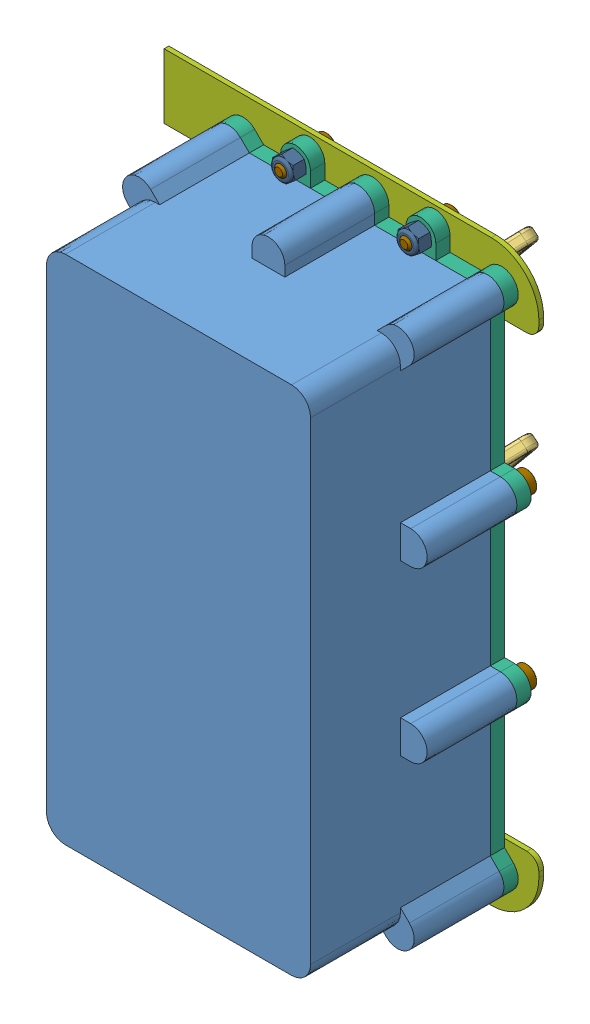
SolidWorks assembly EL-A0101-AA-TSMP + MS Assembly1, configuration Default. Lengths in mm.
Overall size (125.1 193.04 109.98).
49 component instances, 13 part files, 100 mates.
Components (placement in the parent):
- EL-50020-AA-TSMP + MS Enclosure1-1: EL-50020-AA-TSMP + MS Enclosure1 [Default] at (-164.5206 6 19.3259) size (106.02 188.57 59.98)
- EL-000XX-AA-Master Switch1-1: EL-000XX-AA-Master Switch1 [Default] at (-126.4206 74.6871 22.3259) x (-0.7694 0.638768 0) z (0 0 -1) size (57 57 72)
- EL-000XX-AA-Master Switch1-2: EL-000XX-AA-Master Switch1 [Default] at (-126.4206 134.4879 22.3259) x (-0.7694 0.638768 0) z (0 0 -1) size (57 57 72)
- EL-000XX-AA-Master Switch Key1-1: EL-000XX-AA-Master Switch Key1 [Default] at (-128.3369 72.3789 -20.6741) x (-0.7694 0.638768 0) z (0 0 -1) size (9.5 46.9 50)
- EL-000XX-AA-Master Switch Key1-2: EL-000XX-AA-Master Switch Key1 [Default] at (-128.3369 132.1797 -20.6741) x (-0.7694 0.638768 0) z (0 0 -1) size (9.5 46.9 50)
- EL-000XX-AA-Pomona Port (72930)1-1: EL-000XX-AA-Pomona Port (72930)1 [Pomona 72930 (BLACK)] at (-99.7506 103.75 23.6312) x (-0.945625 -0.325259 0) z (0.325259 -0.945625 0) size (14.73 33.88 17.01)
- EL-000XX-AA-Pomona Port (72930)1-2: EL-000XX-AA-Pomona Port (72930)1 [Pomona 72930 (BLACK)] at (-136.5806 23.4625 23.6312) x (0.758926 -0.651177 0) z (0.651177 0.758926 0) size (14.73 33.88 17.01)
- EL-000XX-AA-Pomona Port (72930)1-3: EL-000XX-AA-Pomona Port (72930)1 [Pomona 72930 (RED)] at (-116.2606 23.4625 23.6312) x (-0.998131 0.061106 0) z (-0.061106 -0.998131 0) size (14.73 33.88 17.01)
- EL-500XX-AA-TSMP Cover1-1: EL-500XX-AA-TSMP Cover1 [Default] at (-126.4206 23.4625 8.2134) x (0 0 -1) z (0 -1 0) size (13.97 71.12 30.48)
- EL-60022-AA-Enclosure Lid1-1: EL-60022-AA-Enclosure Lid1 [Default] at (-182.2706 162.971 19.3259) size (106.02 190.75 4.76)
- EL-30021-AA-Enclosure Mounts1-2: EL-30021-AA-Enclosure Mounts1 [Default] at (-133.0715 -19.9201 -386.9408) x (-1 0 0) z (0 0 -1) size (125.1 193.04 1.59)
- FS-Heat Set Insert, M4x7-4.7 (94180A351)-1: FS-Heat Set Insert, M4x7-4.7 (94180A351) [94180A351] at (-169.612 0.9086 21.6759) x (-0.721495 0.69242 0) z (0 0 -1) size (6.35 6.35 4.7)
- BR-Black Oxide C12.9 SHCS, M4x0.7-12 (91290A148)1-1: BR-Black Oxide C12.9 SHCS, M4x0.7-12 (91290A148)1 [91290A148] at (-169.612 0.9086 16.9759) x (0.909602 0.41548 0) z (0 0 -1) size (7 7 16.17)
- FS-Heat Set Insert, M4x7-4.7 (94180A351)-3: FS-Heat Set Insert, M4x7-4.7 (94180A351) [94180A351] at (-126.4206 -3.4097 21.6759) x (-0.990071 -0.140566 0) z (0 0 -1) size (6.35 6.35 4.7)
- BR-Black Oxide C12.9 SHCS, M4x0.7-12 (91290A148)1-3: BR-Black Oxide C12.9 SHCS, M4x0.7-12 (91290A148)1 [91290A148] at (-126.4206 -3.4097 16.9759) x (-1 0 0) z (0 0 -1) size (7 7 16.17)
- FS-Heat Set Insert, M4x7-4.7 (94180A351)-7: FS-Heat Set Insert, M4x7-4.7 (94180A351) [94180A351] at (-173.9303 57.181 21.6759) x (0.930432 0.366464 0) z (0 0 -1) size (6.35 6.35 4.7)
- BR-Black Oxide C12.9 SHCS, M4x0.7-12 (91290A148)1-7: BR-Black Oxide C12.9 SHCS, M4x0.7-12 (91290A148)1 [91290A148] at (-173.9303 57.181 18.5634) x (0.651659 -0.758512 0) z (0 0 -1) size (7 7 16.17)
- BR-Black Oxide C12.9 SHCS, M4x0.7-12 (91290A148)1-12: BR-Black Oxide C12.9 SHCS, M4x0.7-12 (91290A148)1 [91290A148] at (-147.3316 175.75 16.9759) x (0.218887 -0.97575 0) z (0 0 -1) size (7 7 16.17)
- BR-Black Oxide C12.9 SHCS, M4x0.7-12 (91290A148)1-13: BR-Black Oxide C12.9 SHCS, M4x0.7-12 (91290A148)1 [91290A148] at (-147.3316 -5 16.9759) x (-0.84991 0.526928 0) z (0 0 -1) size (7 7 16.17)
- BR-Black Oxide C12.9 SHCS, M4x0.7-12 (91290A148)1-14: BR-Black Oxide C12.9 SHCS, M4x0.7-12 (91290A148)1 [91290A148] at (-105.5097 -5 16.9759) x (-0.836932 0.547307 0) z (0 0 -1) size (7 7 16.17)
- FS-NYLOC C8 HX, M4x0.7-5 (90576A103)1-1: FS-NYLOC C8 HX, M4x0.7-5 (90576A103)1 [90576A103] at (-147.3316 -5 21.8259) size (7 8.08 5)
- FS-NYLOC C8 HX, M4x0.7-5 (90576A103)1-2: FS-NYLOC C8 HX, M4x0.7-5 (90576A103)1 [90576A103] at (-147.3316 175.75 21.8259) x (0.639392 -0.768881 0) z (0 0 1) size (7 8.08 5)
- FS-NYLOC C8 HX, M4x0.7-5 (90576A103)1-3: FS-NYLOC C8 HX, M4x0.7-5 (90576A103)1 [90576A103] at (-105.5097 -5 21.8259) x (0.821981 0.569515 0) z (0 0 1) size (7 8.08 5)
- EL-Steel Nylon Locknut, C8, M6x1-6 (90576A115)1-1: EL-Steel Nylon Locknut, C8, M6x1-6 (90576A115)1 [90576A115] at (-140.6545 146.3051 28.3259) x (0.999355 0.03592 0) z (0 0 1) size (10 11.55 6)
- EL-Steel Nylon Locknut, C8, M6x1-6 (90576A115)1-2: EL-Steel Nylon Locknut, C8, M6x1-6 (90576A115)1 [90576A115] at (-112.1867 122.6707 28.3259) x (-0.960335 0.278849 0) z (0 0 1) size (10 11.55 6)
- EL-BLACK OXIDE C12.9 SHCP, M6x1-22 (91290A328)1-1: EL-BLACK OXIDE C12.9 SHCP, M6x1-22 (91290A328)1 [91290A328] at (-112.1867 122.6707 22.5634) x (-1 0 0) z (0 0 -1) size (10 10 28.07)
- EL-BLACK OXIDE C12.9 SHCP, M6x1-22 (91290A328)1-2: EL-BLACK OXIDE C12.9 SHCP, M6x1-22 (91290A328)1 [91290A328] at (-140.6545 146.3051 22.5634) x (-0.99792 -0.064462 0) z (0 0 -1) size (10 10 28.07)
- EL-BLACK OXIDE C12.9 SHCP, M6x1-22 (91290A328)1-3: EL-BLACK OXIDE C12.9 SHCP, M6x1-22 (91290A328)1 [91290A328] at (-112.1867 62.8699 22.5634) x (-0.99792 -0.064462 0) z (0 0 -1) size (10 10 28.07)
- EL-BLACK OXIDE C12.9 SHCP, M6x1-22 (91290A328)1-4: EL-BLACK OXIDE C12.9 SHCP, M6x1-22 (91290A328)1 [91290A328] at (-140.6545 86.5043 22.5634) x (-0.99792 -0.064462 0) z (0 0 -1) size (10 10 28.07)
- EL-Steel Nylon Locknut, C8, M6x1-6 (90576A115)1-3: EL-Steel Nylon Locknut, C8, M6x1-6 (90576A115)1 [90576A115] at (-112.1867 62.8699 28.3259) x (-0.427051 0.904227 0) z (0 0 1) size (10 11.55 6)
- EL-Steel Nylon Locknut, C8, M6x1-6 (90576A115)1-4: EL-Steel Nylon Locknut, C8, M6x1-6 (90576A115)1 [90576A115] at (-140.6545 86.5043 28.3259) x (-0.279494 0.960147 0) z (0 0 1) size (10 11.55 6)
- BR-Black Oxide C12.9 SHCS, M4x0.7-12 (91290A148)1-15: BR-Black Oxide C12.9 SHCS, M4x0.7-12 (91290A148)1 [91290A148] at (-105.5097 175.75 16.9759) x (0.462086 -0.886835 0) z (0 0 -1) size (7 7 16.17)
- FS-NYLOC C8 HX, M4x0.7-5 (90576A103)1-4: FS-NYLOC C8 HX, M4x0.7-5 (90576A103)1 [90576A103] at (-105.5097 175.75 21.8259) x (-0.393684 -0.919246 0) z (0 0 1) size (7 8.08 5)
- FS-PLASTIC-HEAD THUMB SCREW, M4x0.7-10 (96016A8431-3: FS-PLASTIC-HEAD THUMB SCREW, M4x0.7-10 (96016A8431 [Default] at (-154.3606 23.4625 13.0034) x (0 0 1) z (1 0 0) size (15.5 13 13)
- FS-PLASTIC-HEAD THUMB SCREW, M4x0.7-10 (96016A8431-4: FS-PLASTIC-HEAD THUMB SCREW, M4x0.7-10 (96016A8431 [Default] at (-98.4806 23.4625 13.0034) x (0 0 1) z (1 0 0) size (15.5 13 13)
- FS-Heat Set Insert, M4x7-4.7 (94180A351)-2: FS-Heat Set Insert, M4x7-4.7 (94180A351) [94180A351] at (-83.2293 0.9086 21.6759) x (0.721495 0.69242 0) z (0 0 1) size (6.35 6.35 4.7)
- BR-Black Oxide C12.9 SHCS, M4x0.7-12 (91290A148)1-16: BR-Black Oxide C12.9 SHCS, M4x0.7-12 (91290A148)1 [91290A148] at (-83.2293 0.9086 16.9759) x (0.909602 -0.41548 0) z (0 0 -1) size (7 7 16.17)
- FS-Heat Set Insert, M4x7-4.7 (94180A351)-4: FS-Heat Set Insert, M4x7-4.7 (94180A351) [94180A351] at (-169.612 169.8414 21.6759) x (-0.721495 -0.69242 0) z (0 0 1) size (6.35 6.35 4.7)
- BR-Black Oxide C12.9 SHCS, M4x0.7-12 (91290A148)1-17: BR-Black Oxide C12.9 SHCS, M4x0.7-12 (91290A148)1 [91290A148] at (-169.612 169.8414 16.9759) x (-0.909602 0.41548 0) z (0 0 -1) size (7 7 16.17)
- FS-Heat Set Insert, M4x7-4.7 (94180A351)-5: FS-Heat Set Insert, M4x7-4.7 (94180A351) [94180A351] at (-126.4206 174.1597 21.6759) x (0.990071 -0.140566 0) z (0 0 1) size (6.35 6.35 4.7)
- BR-Black Oxide C12.9 SHCS, M4x0.7-12 (91290A148)1-18: BR-Black Oxide C12.9 SHCS, M4x0.7-12 (91290A148)1 [91290A148] at (-126.4206 174.1597 16.9759) x (1 0 0) z (0 0 -1) size (7 7 16.17)
- BR-Black Oxide C12.9 SHCS, M4x0.7-12 (91290A148)1-19: BR-Black Oxide C12.9 SHCS, M4x0.7-12 (91290A148)1 [91290A148] at (-83.2293 169.8414 16.9759) x (-0.909602 -0.41548 0) z (0 0 -1) size (7 7 16.17)
- FS-Heat Set Insert, M4x7-4.7 (94180A351)-6: FS-Heat Set Insert, M4x7-4.7 (94180A351) [94180A351] at (-83.2293 169.8414 21.6759) x (0.721495 -0.69242 0) z (0 0 -1) size (6.35 6.35 4.7)
- BR-Black Oxide C12.9 SHCS, M4x0.7-12 (91290A148)1-9: BR-Black Oxide C12.9 SHCS, M4x0.7-12 (91290A148)1 [91290A148] at (-173.9303 113.569 18.5634) x (0.651659 -0.758512 0) z (0 0 -1) size (7 7 16.17)
- FS-Heat Set Insert, M4x7-4.7 (94180A351)-9: FS-Heat Set Insert, M4x7-4.7 (94180A351) [94180A351] at (-173.9303 113.569 21.6759) x (0.930432 0.366464 0) z (0 0 -1) size (6.35 6.35 4.7)
- FS-Heat Set Insert, M4x7-4.7 (94180A351)-10: FS-Heat Set Insert, M4x7-4.7 (94180A351) [94180A351] at (-78.9109 57.181 21.6759) x (0.930432 -0.366464 0) z (0 0 1) size (6.35 6.35 4.7)
- BR-Black Oxide C12.9 SHCS, M4x0.7-12 (91290A148)1-20: BR-Black Oxide C12.9 SHCS, M4x0.7-12 (91290A148)1 [91290A148] at (-78.9109 57.181 18.5634) x (0.651659 0.758512 0) z (0 0 -1) size (7 7 16.17)
- FS-Heat Set Insert, M4x7-4.7 (94180A351)-11: FS-Heat Set Insert, M4x7-4.7 (94180A351) [94180A351] at (-78.9109 113.569 21.6759) x (0.930432 -0.366464 0) z (0 0 1) size (6.35 6.35 4.7)
- BR-Black Oxide C12.9 SHCS, M4x0.7-12 (91290A148)1-21: BR-Black Oxide C12.9 SHCS, M4x0.7-12 (91290A148)1 [91290A148] at (-78.9109 113.569 18.5634) x (0.651659 0.758512 0) z (0 0 -1) size (7 7 16.17)
Mates (geometry in assembly coordinates):
- Concentric12: concentric anti-aligned: cylinder of EL-000XX-AA-Master Switch-2 through (-126.4206 134.4879 19.3259) axis (0 0 -1) radius 5; cylinder of EL-000XX-AA-Master Switch Key-2 through (-126.4206 134.4879 -20.6741) axis (0 0 1) radius 4.75
- Coincident7: coincident anti-aligned: plane of EL-000XX-AA-Master Switch-2 through (-126.4206 134.4879 -10.6741) normal (0 0 -1); plane of EL-000XX-AA-Master Switch Key-2 through (-144.6836 109.359 -10.6741) normal (0 0 1)
- Parallel2: parallel: plane of EL-000XX-AA-Master Switch-2 through (-130.3193 131.3574 19.3259) normal (0.7694 -0.638768 0); line of EL-000XX-AA-Master Switch Key-2 through (-128.0152 129.4362 -11.6741) axis (-0.638768 -0.7694 0)
- Concentric18: concentric anti-aligned: cylinder of EL-800XX-BA-HVI Board-1 through (-55.9835 -25.4935 29.8055) axis (0 0 1) radius 2.1; cylinder of FS-NYLON SCREW BHCS, M4x0.7-6(94879A216)-1 through (-155.3975 139.0325 75.2021) axis (0 0 -1) radius 2
- Coincident14: coincident anti-aligned: plane of EL-800XX-BA-HVI Board-1 through (-11.47 -15.016 29.394) normal (0 0 -1); plane of FS-NYLON SCREW BHCS, M4x0.7-6(94879A216)-1 through (-155.3975 139.0325 75.2021) normal (0 0 1)
- Concentric21: concentric anti-aligned: cylinder of EL-000XX-AA-Master Switch-1 through (-126.4206 74.6871 19.3259) axis (0 0 -1) radius 5; cylinder of EL-000XX-AA-Master Switch Key-1 through (-126.4206 74.6871 -20.6741) axis (0 0 1) radius 4.75
- Parallel3: parallel anti-aligned: plane of EL-000XX-AA-Master Switch-1 through (-130.3193 71.5566 19.3259) normal (0.7694 -0.638768 0); plane of EL-000XX-AA-Master Switch Key-1 through (-129.8757 73.6564 -20.6741) normal (-0.7694 0.638768 0)
- Coincident18: coincident anti-aligned: plane of EL-000XX-AA-Master Switch-1 through (-126.4206 74.6871 -10.6741) normal (0 0 -1); plane of EL-000XX-AA-Master Switch Key-1 through (-144.6836 49.5582 -10.6741) normal (0 0 1)
- Concentric22: concentric aligned: cylinder of EL-500XX-AA-TSMP Cover-1 through (-154.3606 23.4625 10.7534) axis (0 0 -1) radius 2.4; cylinder of FS-PLASTIC-HEAD THUMB SCREW, M4x0.7-10 (96016A843-1 through (-154.3606 23.4625 5.2534) axis (0 0 -1) radius 2
- Coincident19: coincident anti-aligned: plane of EL-500XX-AA-TSMP Cover-1 through (-161.9806 13.3025 10.7534) normal (0 0 -1); plane of FS-PLASTIC-HEAD THUMB SCREW, M4x0.7-10 (96016A843-1 through (-151.1962 22.2191 10.7534) normal (0 0 1)
- Concentric23: concentric aligned: cylinder of EL-500XX-AA-TSMP Cover-1 through (-98.4806 23.4625 10.7534) axis (0 0 -1) radius 2.4; cylinder of FS-PLASTIC-HEAD THUMB SCREW, M4x0.7-10 (96016A843-2 through (-98.4806 23.4625 5.2534) axis (0 0 -1) radius 2
- Coincident20: coincident anti-aligned: plane of EL-500XX-AA-TSMP Cover-1 through (-90.8606 13.3025 10.7534) normal (0 0 -1); plane of FS-PLASTIC-HEAD THUMB SCREW, M4x0.7-10 (96016A843-2 through (-99.8556 26.5721 10.7534) normal (0 0 1)
- Coincident27: coincident anti-aligned: plane of EL-500XX-CA-TSMP Enclosure-1 through (-155.3975 139.0325 75.8259) normal (0 0 -1); plane of EL-800XX-AA-TelemHost Board-1 through (-109.9315 108.0445 75.8259) normal (0 0 1)
- Distance2: distance = 1.5875 mm: plane of EL-500XX-CA-TSMP Enclosure-1 through (-164.5206 164.75 73.3009) normal (0 -1 0); line of EL-800XX-AA-TelemHost Board-1 through (-160.4775 144.1125 75.2021) axis (1 0 0)
- Tangent2: tangent anti-aligned: torus of EL-500XX-CA-TSMP Enclosure-1 through (-164.5206 6 73.3009) normal (1 0 0); edge_curve of EL-800XX-AA-TelemHost Board-1
- Coincident35: coincident anti-aligned: plane of EL-500XX-CA-TSMP Enclosure-1 through (-164.5206 0 73.3009) normal (0 -1 0)
- Coincident38: coincident anti-aligned: plane of EL-60022-AA-Enclosure Lid-1 through (-169.612 169.8414 19.3259) normal (0 0 1); plane of EL-000XX-AA-Master Switch-1 through (-126.4206 74.6871 19.3259) normal (0 0 -1)
- Coincident39: coincident anti-aligned: plane of EL-60022-AA-Enclosure Lid-1 through (-169.612 169.8414 19.3259) normal (0 0 1); plane of EL-000XX-AA-Master Switch-2 through (-126.4206 134.4879 19.3259) normal (0 0 -1)
- Coincident40: coincident anti-aligned: plane of EL-60022-AA-Enclosure Lid-1 through (-169.612 169.8414 14.5634) normal (0 0 -1); plane of EL-500XX-AA-TSMP Cover-1 through (-141.6606 33.6225 14.5634) normal (0 0 1)
- Coincident42: coincident anti-aligned: plane of EL-60022-AA-Enclosure Lid-1 through (-169.612 169.8414 14.5634) normal (0 0 -1); plane of EL-000XX-AA-Pomona Port (72930)-2 through (-141.3772 17.8723 14.5634) normal (0 0 1)
- Coincident43: coincident anti-aligned: plane of EL-60022-AA-Enclosure Lid-1 through (-169.612 169.8414 14.5634) normal (0 0 -1); plane of EL-000XX-AA-Pomona Port (72930)-3 through (-115.8105 30.8147 14.5634) normal (0 0 1)
- Concentric39: concentric aligned: cylinder of FS-Heat Set Insert, M4x7-4.7 (94180A351)-1 through (-169.612 0.9086 19.3259) axis (0 0 -1) radius 2; cylinder of FS-NYLON SCREW BHCS, M4x0.7-6(94879A216)-1 through (-155.3975 139.0325 75.2021) axis (0 0 -1) radius 2
- Coincident50: coincident anti-aligned: plane of EL-800XX-AA-TelemHost Board-1 through (-109.9315 108.0445 75.2021) normal (0 0 -1); plane of FS-NYLON SCREW BHCS, M4x0.7-6(94879A216)-1 through (-155.3975 139.0325 75.2021) normal (0 0 1)
- Coincident51: coincident anti-aligned: plane of EL-300XX-CA-TSMP Tab-1 through (-133.0715 -19.9201 17.7384) normal (0 0 -1); plane of BR-Black Oxide C12.9 SHCS, M4x0.7-12 (91290A148)-1 through (-168.2409 -2.0931 12.9759) normal (0 0 1)
- Concentric41: concentric aligned: cylinder of EL-500XX-CA-TSMP Enclosure-1 through (-173.9303 57.181 28.3259) axis (0 0 -1) radius 3.025; cylinder of FS-Heat Set Insert, M4x7-4.7 (94180A351)-20 through (-173.9303 58.705 19.3259) axis (0 0 -1) radius 3.175
- Coincident52: coincident aligned: plane of EL-500XX-CA-TSMP Enclosure-1 through (-164.5206 6 19.3259) normal (0 0 -1); plane of FS-Heat Set Insert, M4x7-4.7 (94180A351)-20 through (-171.9307 58.7435 19.3259) normal (0 0 -1)
- Concentric42: concentric: cylinder of FS-Heat Set Insert, M4x7-4.7 (94180A351)-20 through (-173.9303 58.705 19.3259) axis (0 0 -1) radius 2; cylinder of BR-Black Oxide C12.9 SHCS, M4x0.7-12 (91290A148)-14 through (-105.5097 -5 24.9759) axis (0 0 1) radius 2
- Coincident54: coincident: plane of EL-300XX-CA-TSMP Tab-1 through (-133.0715 -19.9201 17.7384) normal (0 0 -1); plane of BR-Black Oxide C12.9 SHCS, M4x0.7-12 (91290A148)-14 through (-103.7036 -2.2381 12.9759) normal (0 0 1)
- Concentric43: concentric aligned: cylinder of EL-500XX-CA-TSMP Enclosure-1 through (-169.612 169.8414 28.3259) axis (0 0 -1) radius 3.025; cylinder of EL-300XX-CA-TSMP Tab-1 through (-169.612 169.8414 17.7384) axis (0 0 -1) radius 2.25
- Concentric44: concentric aligned: cylinder of EL-500XX-CA-TSMP Enclosure-1 through (-83.2293 0.9086 28.3259) axis (0 0 -1) radius 3.025; cylinder of EL-300XX-CA-TSMP Tab-1 through (-83.2293 0.9086 17.7384) axis (0 0 -1) radius 2.25
- Concentric45: concentric anti-aligned: cylinder of EL-300XX-CA-TSMP Tab-1 through (-99.7506 103.75 19.3259) axis (0 0 -1) radius 6.477; cylinder of EL-000XX-AA-Pomona Port (72930)-1 through (-99.7506 103.75 35.6454) axis (0 0 1) radius 5.842
- Coincident55: coincident anti-aligned: plane of EL-60022-AA-Enclosure Lid-1 through (-169.612 169.8414 14.5634) normal (0 0 -1); plane of EL-000XX-AA-Pomona Port (72930)-1 through (-102.1465 110.7155 14.5634) normal (0 0 1)
- Coincident62: coincident anti-aligned: plane of EL-500XX-CA-TSMP Enclosure-1 through (-164.5206 6 19.3259) normal (0 0 -1); plane of EL-60022-AA-Enclosure Lid-1 through (-182.2706 162.971 19.3259) normal (0 0 1)
- Coincident63: coincident aligned: plane of EL-500XX-CA-TSMP Enclosure-1 through (-164.5206 170.75 73.3009) normal (0 1 0); plane of EL-60022-AA-Enclosure Lid-1 through (-131.9206 170.75 14.5634) normal (0 1 0)
- Coincident64: coincident aligned: plane of EL-500XX-CA-TSMP Enclosure-1 through (-82.3206 6 73.3009) normal (1 0 0); plane of EL-60022-AA-Enclosure Lid-1 through (-82.3206 119.069 14.5634) normal (1 0 0)
- Coincident69: coincident anti-aligned: plane of EL-300XX-CA-TSMP Tab-1 through (-133.0715 -19.9201 19.3259) normal (0 0 1); plane of EL-60022-AA-Enclosure Lid-1 through (-169.612 169.8414 14.5634) normal (0 0 -1)
- Coincident71: coincident anti-aligned: plane of EL-60022-AA-Enclosure Lid-1 through (-169.612 169.8414 14.5634) normal (0 0 -1); plane of EL-30021-AA-Enclosure Mounts-2 through (-133.0715 -19.9201 14.5634) normal (0 0 1)
- Concentric55: concentric aligned: cylinder of EL-60022-AA-Enclosure Lid-1 through (-169.612 169.8414 14.5634) axis (0 0 -1) radius 2.25; cylinder of EL-30021-AA-Enclosure Mounts-2 through (-169.612 169.8414 12.9759) axis (0 0 -1) radius 2.25
- Concentric56: concentric aligned: cylinder of EL-60022-AA-Enclosure Lid-1 through (-83.2293 0.9086 14.5634) axis (0 0 -1) radius 2.25; cylinder of EL-30021-AA-Enclosure Mounts-2 through (-83.2293 0.9086 12.9759) axis (0 0 -1) radius 2.25
- Concentric57: concentric anti-aligned: cylinder of EL-000XX-AA-Pomona Port (72930)-2 through (-136.5806 23.4625 35.6454) axis (0 0 1) radius 7.366; cylinder of EL-60022-AA-Enclosure Lid-1 through (-136.5806 23.4625 19.3259) axis (0 0 -1) radius 6.445
- Concentric58: concentric anti-aligned: cylinder of EL-000XX-AA-Pomona Port (72930)-3 through (-116.2606 23.4625 35.6454) axis (0 0 1) radius 7.366; cylinder of EL-60022-AA-Enclosure Lid-1 through (-116.2606 23.4625 19.3259) axis (0 0 -1) radius 6.445
- Concentric59: concentric aligned: cylinder of FS-PLASTIC-HEAD THUMB SCREW, M4x0.7-10 (96016A843-2 through (-98.4806 23.4625 5.2534) axis (0 0 -1) radius 2; cylinder of EL-60022-AA-Enclosure Lid-1 through (-98.4806 23.4625 19.3259) axis (0 0 -1) radius 2.9766
- Concentric60: concentric aligned: cylinder of FS-PLASTIC-HEAD THUMB SCREW, M4x0.7-10 (96016A843-1 through (-154.3606 23.4625 5.2534) axis (0 0 -1) radius 2; cylinder of EL-60022-AA-Enclosure Lid-1 through (-154.3606 23.4625 19.3259) axis (0 0 -1) radius 2.9766
- Concentric61: concentric anti-aligned: cylinder of EL-000XX-AA-Pomona Port (72930)-1 through (-99.7506 103.75 35.6454) axis (0 0 1) radius 7.366; cylinder of EL-60022-AA-Enclosure Lid-1 through (-99.7506 103.75 19.3259) axis (0 0 -1) radius 6.445
- Concentric62: concentric aligned: cylinder of EL-500XX-CA-TSMP Enclosure-1 through (-169.612 0.9086 28.3259) axis (0 0 -1) radius 3.025; cylinder of FS-Heat Set Insert, M4x7-4.7 (94180A351)-1 through (-169.612 0.9086 19.3259) axis (0 0 -1) radius 2
- Coincident72: coincident aligned: plane of EL-500XX-CA-TSMP Enclosure-1 through (-164.5206 6 19.3259) normal (0 0 -1); plane of FS-Heat Set Insert, M4x7-4.7 (94180A351)-1 through (-168.2272 2.3516 19.3259) normal (0 0 -1)
- Concentric63: concentric anti-aligned: cylinder of EL-30021-AA-Enclosure Mounts-2 through (-169.612 0.9086 12.9759) axis (0 0 -1) radius 2.25; cylinder of BR-Black Oxide C12.9 SHCS, M4x0.7-12 (91290A148)-1 through (-169.612 0.9086 24.9759) axis (0 0 1) radius 2
- Coincident73: coincident anti-aligned: plane of EL-30021-AA-Enclosure Mounts-2 through (-133.0715 -19.9201 12.9759) normal (0 0 -1); plane of BR-Black Oxide C12.9 SHCS, M4x0.7-12 (91290A148)-1 through (-168.2409 -2.0931 12.9759) normal (0 0 1)
- Concentric64: concentric aligned: cylinder of EL-500XX-CA-TSMP Enclosure-1 through (-126.4206 -3.4097 28.3259) axis (0 0 -1) radius 3.025; cylinder of FS-Heat Set Insert, M4x7-4.7 (94180A351)-3 through (-126.4206 -3.4097 19.3259) axis (0 0 -1) radius 2
- Coincident75: coincident aligned: plane of EL-500XX-CA-TSMP Enclosure-1 through (-164.5206 6 19.3259) normal (0 0 -1); plane of FS-Heat Set Insert, M4x7-4.7 (94180A351)-3 through (-126.7018 -1.4296 19.3259) normal (0 0 -1)
- Concentric66: concentric anti-aligned: cylinder of FS-Heat Set Insert, M4x7-4.7 (94180A351)-3 through (-126.4206 -3.4097 19.3259) axis (0 0 -1) radius 2; cylinder of BR-Black Oxide C12.9 SHCS, M4x0.7-12 (91290A148)-3 through (-126.4206 -3.4097 24.9759) axis (0 0 1) radius 2
- Coincident76: coincident anti-aligned: plane of EL-30021-AA-Enclosure Mounts-2 through (-133.0715 -19.9201 12.9759) normal (0 0 -1); plane of BR-Black Oxide C12.9 SHCS, M4x0.7-12 (91290A148)-3 through (-126.4206 -0.1097 12.9759) normal (0 0 1)
- Concentric67: concentric aligned: cylinder of EL-500XX-CA-TSMP Enclosure-1 through (-173.9303 57.181 28.3259) axis (0 0 -1) radius 3.025; cylinder of FS-Heat Set Insert, M4x7-4.7 (94180A351)-7 through (-173.9303 57.181 19.3259) axis (0 0 -1) radius 2
- Coincident78: coincident aligned: plane of EL-500XX-CA-TSMP Enclosure-1 through (-164.5206 6 19.3259) normal (0 0 -1); plane of FS-Heat Set Insert, M4x7-4.7 (94180A351)-7 through (-173.1974 55.3201 19.3259) normal (0 0 -1)
- Concentric68: concentric anti-aligned: cylinder of FS-Heat Set Insert, M4x7-4.7 (94180A351)-7 through (-173.9303 57.181 19.3259) axis (0 0 -1) radius 2; cylinder of BR-Black Oxide C12.9 SHCS, M4x0.7-12 (91290A148)-7 through (-173.9303 57.181 26.5634) axis (0 0 1) radius 2
- Coincident79: coincident anti-aligned: plane of EL-60022-AA-Enclosure Lid-1 through (-169.612 169.8414 14.5634) normal (0 0 -1); plane of BR-Black Oxide C12.9 SHCS, M4x0.7-12 (91290A148)-7 through (-176.4334 55.0305 14.5634) normal (0 0 1)
- Concentric69: concentric: cylinder of EL-60022-AA-Enclosure Lid-1 through (-147.3316 175.75 19.3259) axis (0 0 1) radius 2.25; cylinder of BR-Black Oxide C12.9 SHCS, M4x0.7-8 (91290A140)-1 through (-147.3316 175.75 20.9759) axis (0 0 1) radius 2
- Coincident80: coincident anti-aligned: plane of EL-30021-AA-Enclosure Mounts-2 through (-133.0715 -19.9201 12.9759) normal (0 0 -1); plane of BR-Black Oxide C12.9 SHCS, M4x0.7-8 (91290A140)-1 through (-147.3316 179.05 12.9759) normal (0 0 1)
- Concentric70: concentric anti-aligned: cylinder of EL-30021-AA-Enclosure Mounts-2 through (-147.3316 175.75 12.9759) axis (0 0 -1) radius 2.25; cylinder of BR-Black Oxide C12.9 SHCS, M4x0.7-12 (91290A148)-12 through (-147.3316 175.75 24.9759) axis (0 0 1) radius 2
- Coincident81: coincident anti-aligned: circle of EL-30021-AA-Enclosure Mounts-2; circle of BR-Black Oxide C12.9 SHCS, M4x0.7-12 (91290A148)-12
- Coincident82: coincident anti-aligned: plane of EL-30021-AA-Enclosure Mounts-2 through (-133.0715 -19.9201 12.9759) normal (0 0 -1); plane of BR-Black Oxide C12.9 SHCS, M4x0.7-12 (91290A148)-13 through (-145.5927 -2.1953 12.9759) normal (0 0 1)
- Coincident83: coincident anti-aligned: plane of EL-30021-AA-Enclosure Mounts-2 through (-133.0715 -19.9201 12.9759) normal (0 0 -1); plane of BR-Black Oxide C12.9 SHCS, M4x0.7-12 (91290A148)-14 through (-103.7036 -2.2381 12.9759) normal (0 0 1)
- Concentric74: concentric anti-aligned: cylinder of BR-Black Oxide C12.9 SHCS, M4x0.7-12 (91290A148)-13 through (-147.3316 -5 24.9759) axis (0 0 1) radius 2; cylinder of FS-NYLOC C8 HX, M4x0.7-5 (90576A103)-1 through (-147.3316 -5 24.3259) axis (0 0 -1) radius 2
- Coincident84: coincident anti-aligned: plane of EL-60022-AA-Enclosure Lid-1 through (-169.612 169.8414 19.3259) normal (0 0 1); plane of FS-NYLOC C8 HX, M4x0.7-5 (90576A103)-1 through (-147.3316 -5 19.3259) normal (0 0 -1)
- Concentric75: concentric anti-aligned: cylinder of BR-Black Oxide C12.9 SHCS, M4x0.7-12 (91290A148)-12 through (-147.3316 175.75 24.9759) axis (0 0 1) radius 2; cylinder of FS-NYLOC C8 HX, M4x0.7-5 (90576A103)-2 through (-147.3316 175.75 24.3259) axis (0 0 -1) radius 2
- Coincident85: coincident anti-aligned: plane of EL-60022-AA-Enclosure Lid-1 through (-169.612 169.8414 19.3259) normal (0 0 1); plane of FS-NYLOC C8 HX, M4x0.7-5 (90576A103)-2 through (-147.3316 175.75 19.3259) normal (0 0 -1)
- Concentric76: concentric anti-aligned: cylinder of BR-Black Oxide C12.9 SHCS, M4x0.7-12 (91290A148)-14 through (-105.5097 -5 24.9759) axis (0 0 1) radius 2; cylinder of FS-NYLOC C8 HX, M4x0.7-5 (90576A103)-3 through (-105.5097 -5 24.3259) axis (0 0 -1) radius 2
- Coincident86: coincident anti-aligned: plane of EL-60022-AA-Enclosure Lid-1 through (-169.612 169.8414 19.3259) normal (0 0 1); plane of FS-NYLOC C8 HX, M4x0.7-5 (90576A103)-3 through (-105.5097 -5 19.3259) normal (0 0 -1)
- Concentric77: concentric anti-aligned: cylinder of EL-600XX-AA-TSMP Enclosure Acrylic Lid-1 through (-107.9206 134.4879 19.3259) axis (0 0 -1) radius 4.5; cylinder of FS-BLACK-OXIDE C12.9 SHCS, M8x1.25-30 (91290A434)-1 through (-107.9206 134.4879 44.4122) axis (0 0 1) radius 4
- Concentric80: concentric anti-aligned: cylinder of EL-000XX-AA-Master Switch-2 through (-126.4206 134.4879 -10.6741) axis (0 0 1) radius 10; cylinder of EL-60022-AA-Enclosure Lid-1 through (-126.4206 134.4879 19.3259) axis (0 0 -1) radius 11.9
- Concentric81: concentric anti-aligned: cylinder of EL-000XX-AA-Master Switch-1 through (-126.4206 74.6871 -10.6741) axis (0 0 1) radius 10; cylinder of EL-60022-AA-Enclosure Lid-1 through (-126.4206 74.6871 19.3259) axis (0 0 -1) radius 11.9
- Angle4: planar angle = 0.877901 rad anti-aligned: plane of EL-000XX-AA-Master Switch-2 through (-126.4206 134.4879 22.3259) normal (0.638768 0.7694 0); plane of EL-30021-AA-Enclosure Mounts-2 through (-195.9531 181.895 14.5634) normal (-1 0 0)
- Parallel8: parallel aligned: plane of EL-000XX-AA-Master Switch Key-1 through (-127.5675 71.7401 -20.6741) normal (0.7694 -0.638768 0); plane of EL-000XX-AA-Master Switch Key-2 through (-127.5675 131.541 -20.6741) normal (0.7694 -0.638768 0)
- Coincident90: coincident anti-aligned: plane of EL-000XX-AA-Master Switch-2 through (-126.4206 134.4879 25.3259) normal (0 0 1); plane of 90576A115_Medium-Strength Steel Nylon-Insert Locknut-1 through (-140.6545 146.3051 25.3259) normal (0 0 -1)
- Coincident91: coincident anti-aligned: plane of EL-000XX-AA-Master Switch-2 through (-126.4206 134.4879 25.3259) normal (0 0 1); plane of 90576A115_Medium-Strength Steel Nylon-Insert Locknut-2 through (-112.1867 122.6707 25.3259) normal (0 0 -1)
- Concentric88: concentric anti-aligned: cylinder of EL-60022-AA-Enclosure Lid-1 through (-112.1867 122.6707 19.3259) axis (0 0 -1) radius 3.3; cylinder of 91290A328_Alloy Steel Socket Head Screw-1 through (-112.1867 122.6707 36.5634) axis (0 0 1) radius 3
- Coincident92: coincident anti-aligned: plane of EL-60022-AA-Enclosure Lid-1 through (-169.612 169.8414 14.5634) normal (0 0 -1); plane of 91290A328_Alloy Steel Socket Head Screw-1 through (-112.1867 127.3707 14.5634) normal (0 0 1)
- Concentric89: concentric anti-aligned: cylinder of 90576A115_Medium-Strength Steel Nylon-Insert Locknut-2 through (-112.1867 122.6707 25.3259) axis (0 0 -1) radius 2.3505; cylinder of 91290A328_Alloy Steel Socket Head Screw-1 through (-112.1867 122.6707 36.5634) axis (0 0 1) radius 3
- Concentric90: concentric anti-aligned: cylinder of EL-60022-AA-Enclosure Lid-1 through (-140.6545 146.3051 19.3259) axis (0 0 -1) radius 3.3; cylinder of 91290A328_Alloy Steel Socket Head Screw-2 through (-140.6545 146.3051 36.5634) axis (0 0 1) radius 3
- Coincident93: coincident anti-aligned: plane of EL-60022-AA-Enclosure Lid-1 through (-169.612 169.8414 14.5634) normal (0 0 -1); plane of 91290A328_Alloy Steel Socket Head Screw-2 through (-140.9575 150.9953 14.5634) normal (0 0 1)
- Concentric91: concentric anti-aligned: cylinder of EL-60022-AA-Enclosure Lid-1 through (-112.1867 62.8699 19.3259) axis (0 0 -1) radius 3.3; cylinder of 91290A328_Alloy Steel Socket Head Screw-3 through (-112.1867 62.8699 36.5634) axis (0 0 1) radius 3
- Coincident94: coincident anti-aligned: plane of EL-60022-AA-Enclosure Lid-1 through (-169.612 169.8414 14.5634) normal (0 0 -1); plane of 91290A328_Alloy Steel Socket Head Screw-3 through (-112.4897 67.5601 14.5634) normal (0 0 1)
- Concentric92: concentric anti-aligned: cylinder of EL-60022-AA-Enclosure Lid-1 through (-140.6545 86.5043 19.3259) axis (0 0 -1) radius 3.3; cylinder of 91290A328_Alloy Steel Socket Head Screw-4 through (-140.6545 86.5043 36.5634) axis (0 0 1) radius 3
- Coincident95: coincident anti-aligned: plane of EL-60022-AA-Enclosure Lid-1 through (-169.612 169.8414 14.5634) normal (0 0 -1); plane of 91290A328_Alloy Steel Socket Head Screw-4 through (-140.9575 91.1945 14.5634) normal (0 0 1)
- Concentric93: concentric anti-aligned: cylinder of 91290A328_Alloy Steel Socket Head Screw-3 through (-112.1867 62.8699 36.5634) axis (0 0 1) radius 3; cylinder of 90576A115_Medium-Strength Steel Nylon-Insert Locknut-3 through (-112.1867 62.8699 31.3259) axis (0 0 -1) radius 3
- Coincident96: coincident anti-aligned: plane of EL-000XX-AA-Master Switch-1 through (-126.4206 74.6871 25.3259) normal (0 0 1); plane of 90576A115_Medium-Strength Steel Nylon-Insert Locknut-3 through (-112.1867 62.8699 25.3259) normal (0 0 -1)
- Concentric94: concentric anti-aligned: cylinder of 91290A328_Alloy Steel Socket Head Screw-4 through (-140.6545 86.5043 36.5634) axis (0 0 1) radius 3; cylinder of 90576A115_Medium-Strength Steel Nylon-Insert Locknut-4 through (-140.6545 86.5043 31.3259) axis (0 0 -1) radius 3
- Coincident97: coincident anti-aligned: plane of EL-000XX-AA-Master Switch-1 through (-126.4206 74.6871 25.3259) normal (0 0 1); plane of 90576A115_Medium-Strength Steel Nylon-Insert Locknut-4 through (-140.6545 86.5043 25.3259) normal (0 0 -1)
- Concentric95: concentric aligned: cylinder of EL-60022-AA-Enclosure Lid-1 through (-105.5097 -5 19.3259) axis (0 0 1) radius 2.25; cylinder of BR-Black Oxide C12.9 SHCS, M4x0.7-12 (91290A148)-14 through (-105.5097 -5 24.9759) axis (0 0 1) radius 2
- Concentric96: concentric anti-aligned: cylinder of EL-30021-AA-Enclosure Mounts-2 through (-105.5097 175.75 14.5634) axis (0 0 -1) radius 2.25; cylinder of BR-Black Oxide C12.9 SHCS, M4x0.7-12 (91290A148)-15 through (-105.5097 175.75 24.9759) axis (0 0 1) radius 2
- Coincident98: coincident anti-aligned: plane of EL-30021-AA-Enclosure Mounts-2 through (-133.0715 -19.9201 12.9759) normal (0 0 -1); plane of BR-Black Oxide C12.9 SHCS, M4x0.7-12 (91290A148)-15 through (-108.4363 174.2251 12.9759) normal (0 0 1)
- Concentric97: concentric anti-aligned: cylinder of EL-30021-AA-Enclosure Mounts-2 through (-147.3316 -5 14.5634) axis (0 0 -1) radius 2.25; cylinder of BR-Black Oxide C12.9 SHCS, M4x0.7-12 (91290A148)-13 through (-147.3316 -5 24.9759) axis (0 0 1) radius 2
- Concentric98: concentric anti-aligned: cylinder of BR-Black Oxide C12.9 SHCS, M4x0.7-12 (91290A148)-15 through (-105.5097 175.75 24.9759) axis (0 0 1) radius 2; cylinder of FS-NYLOC C8 HX, M4x0.7-5 (90576A103)-4 through (-105.5097 175.75 24.3259) axis (0 0 -1) radius 2
- Coincident99: coincident anti-aligned: plane of EL-60022-AA-Enclosure Lid-1 through (-169.612 169.8414 19.3259) normal (0 0 1); plane of FS-NYLOC C8 HX, M4x0.7-5 (90576A103)-4 through (-105.5097 175.75 19.3259) normal (0 0 -1)
- Concentric99: concentric aligned: cylinder of EL-500XX-AA-TSMP Cover-1 through (-154.3606 23.4625 10.7534) axis (0 0 -1) radius 2.4; cylinder of EL-60022-AA-Enclosure Lid-1 through (-154.3606 23.4625 19.3259) axis (0 0 -1) radius 2.9766
- Concentric100: concentric aligned: cylinder of EL-500XX-AA-TSMP Cover-1 through (-98.4806 23.4625 10.7534) axis (0 0 -1) radius 2.4; cylinder of EL-60022-AA-Enclosure Lid-1 through (-98.4806 23.4625 19.3259) axis (0 0 -1) radius 2.9766
- Concentric101: concentric aligned: cylinder of EL-500XX-AA-TSMP Cover-1 through (-154.3606 23.4625 10.7534) axis (0 0 -1) radius 2.4; cylinder of FS-PLASTIC-HEAD THUMB SCREW, M4x0.7-10 (96016A843-3 through (-154.3606 23.4625 5.2534) axis (0 0 -1) radius 2
- Coincident100: coincident anti-aligned: plane of EL-500XX-AA-TSMP Cover-1 through (-161.9806 13.3025 10.7534) normal (0 0 -1); plane of FS-PLASTIC-HEAD THUMB SCREW, M4x0.7-10 (96016A843-3 through (-154.3606 18.5625 10.7534) normal (0 0 1)
- Concentric102: concentric aligned: cylinder of EL-500XX-AA-TSMP Cover-1 through (-98.4806 23.4625 10.7534) axis (0 0 -1) radius 2.4; cylinder of FS-PLASTIC-HEAD THUMB SCREW, M4x0.7-10 (96016A843-4 through (-98.4806 23.4625 5.2534) axis (0 0 -1) radius 2
- Coincident101: coincident anti-aligned: plane of EL-500XX-AA-TSMP Cover-1 through (-90.8606 13.3025 10.7534) normal (0 0 -1); plane of FS-PLASTIC-HEAD THUMB SCREW, M4x0.7-10 (96016A843-4 through (-98.4806 18.5625 10.7534) normal (0 0 1)
